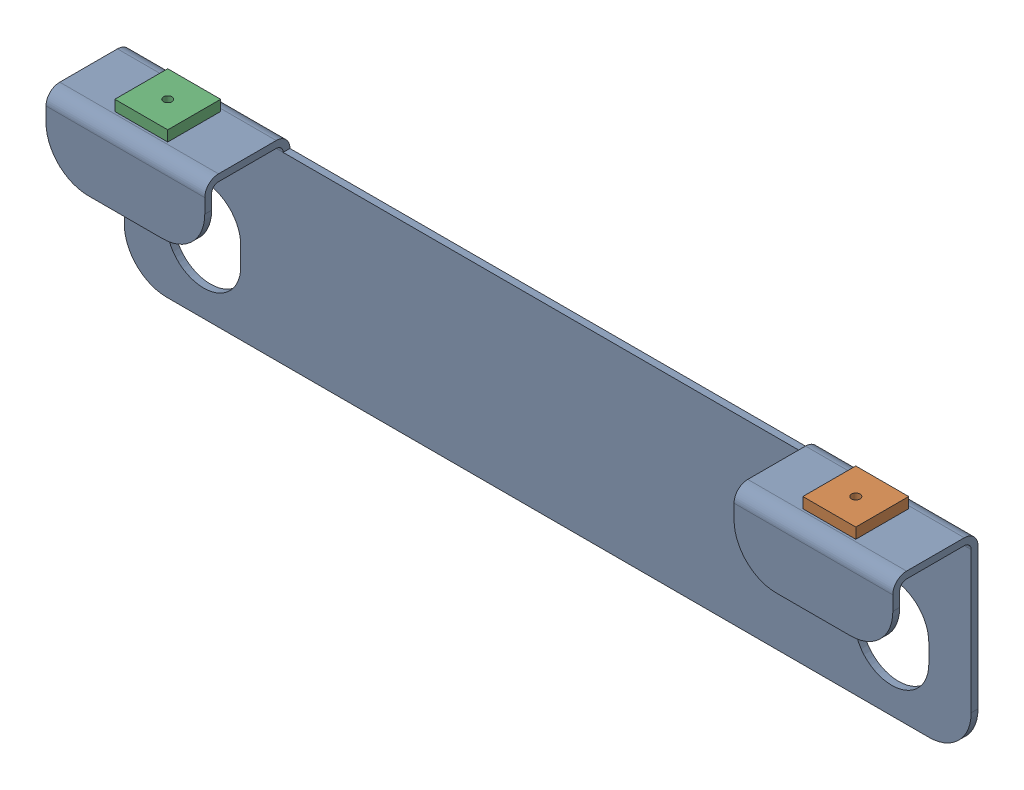
SolidWorks assembly GE-15021_ASM, configuration Default. Lengths in mm.
Overall size (508 124.76 51.09).
3 component instances, 2 part files, 0 mates.
Components (placement in the parent):
- GE-15021-01-1: GE-15021-01 [Default] at origin size (508 118.41 51.09)
- GE-15021-02-1: GE-15021-02 [Default] at (206.375 4.1148 -21.2852) size (31.75 6.35 31.75)
- GE-15021-02-2: GE-15021-02 [Default] at (-206.375 4.1148 -21.2852) x (-1 0 0) z (0 0 -1) size (31.75 6.35 31.75)
